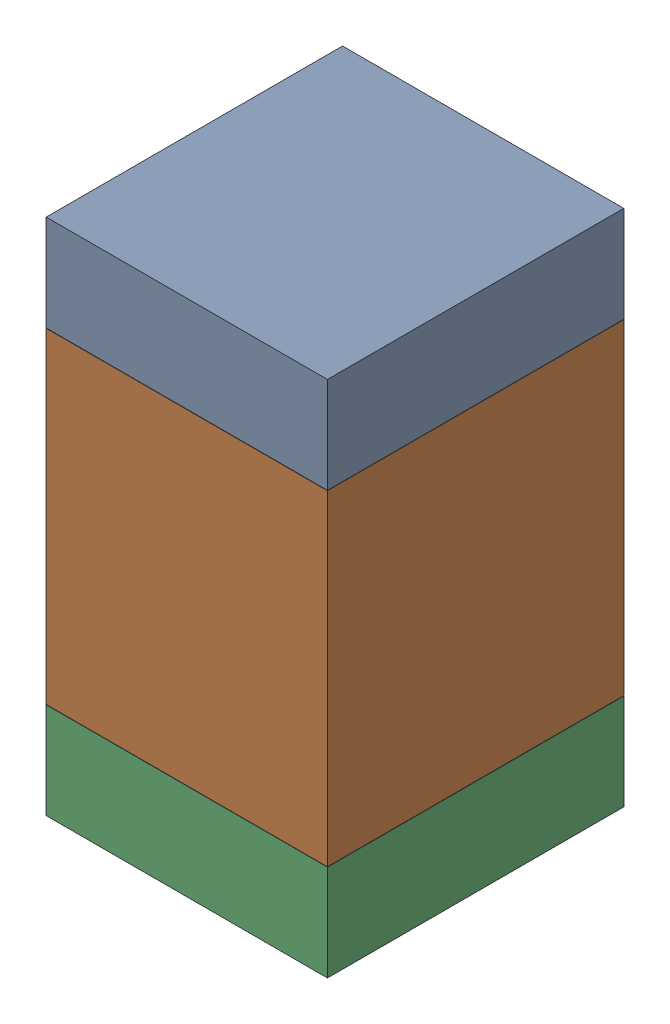
SolidWorks assembly R31, configuration Default. Lengths in mm.
Overall size (0.95 1.75 1).
6 component instances, 2 part files, 0 mates.
Components (placement in the parent):
- 6575495072-1: 6575495072 [Default] at (41.91 6.8085 0) size (0.95 0.32 1)
  - Extruded_6-1: Extruded_6 [Default] at origin size (0.95 0.32 1)
- 6575494912-1: 6575494912 [Default] at (41.91 6.096 0) size (0.95 1.1 1)
  - Extruded_7-1: Extruded_7 [Default] at origin size (0.95 1.1 1)
- 6575495072-2: 6575495072 [Default] at (41.91 5.3835 0) size (0.95 0.32 1)
  - Extruded_6-1: Extruded_6 [Default] at origin size (0.95 0.32 1)
